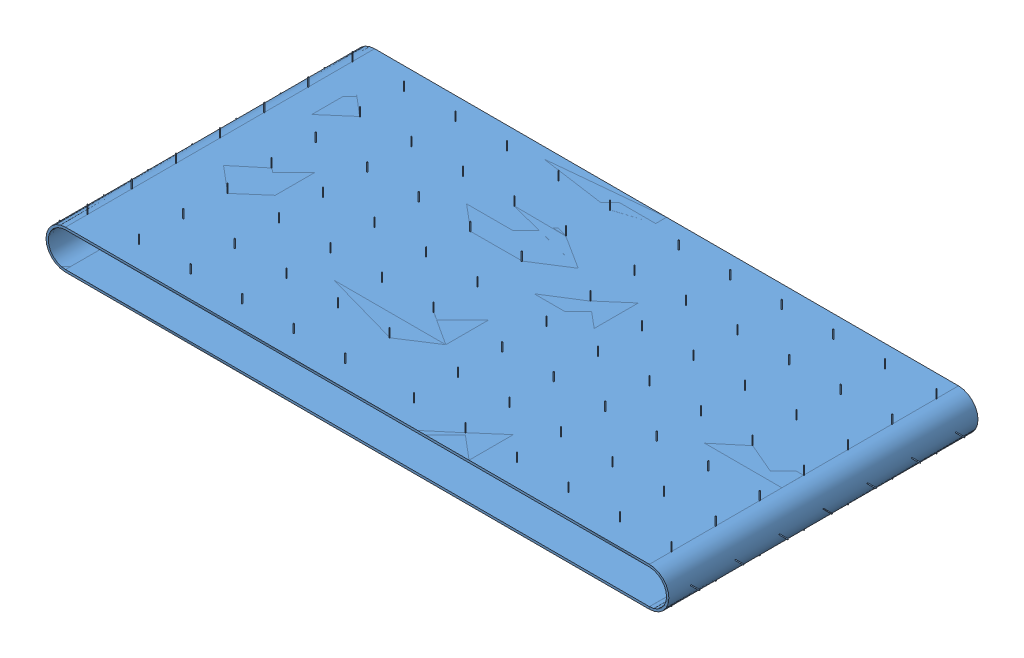
SolidWorks assembly MQP_belt assembly, configuration Default. Lengths in mm.
Overall size (953 89.41 457.2).
2 component instances, 1 part files, 4 mates.
Components (placement in the parent):
- MQP_belt-1: MQP_belt [Default] at origin size (953 89.41 457.2)
- MQP_belt-2: MQP_belt [Default] at origin size (953 89.41 457.2)
Mates (geometry in assembly coordinates):
- Coincident1: coincident anti-aligned: plane of MQP_belt-1 through (431.8 -25.4 228.6) normal (0 1 0); plane of 7959K25_Timing Belt-5 through (-426.72 -25.4 228.6) normal (0 -1 0)
- Coincident2: coincident aligned: plane of MQP_belt-1 through (431.8 0 228.6) normal (0 0 1); plane of 7959K25_Timing Belt-5 through (-427.8534 -24.2094 228.6) normal (0 0 1)
- Coincident5: coincident aligned: line of MQP_belt-1 through (-431.8 -25.4 228.6) axis (0 0 -1); line of 7959K25_Timing Belt-5 through (-431.8 -25.4 228.6) axis (0 0 -1)
- Coincident31: coordinate: point of MQP_belt-1
